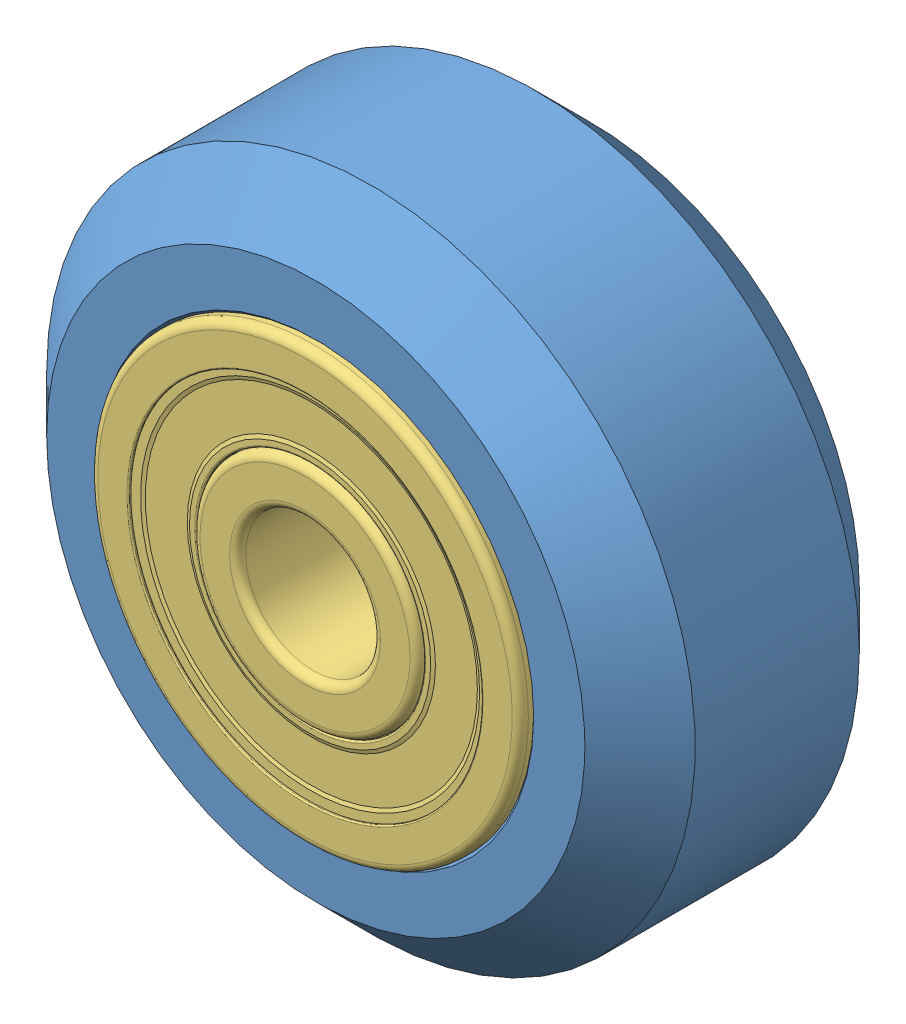
SolidWorks assembly V Wheel Component, configuration 默认. Lengths in mm.
Overall size (24.1 24.1 11.01).
4 component instances, 3 part files, 7 mates.
Components (placement in the parent):
- Rollers-1: Rollers [默认] at (1.8311 31.528 37.55) size (24.1 24.1 10.2)
- M5 washer1-1: M5 washer1 [默认] at (17.3311 -3.972 23.6) size (10 10 1)
- 625pillow-1: 625pillow [默认] at (17.3311 -3.972 21.1) x (0 0 1) z (-1 0 0) size (5.01 16 16)
- 625pillow-2: 625pillow [默认] at (17.3311 -3.972 27.1) x (0 0 -1) z (1 0 0) size (5.01 16 16)
Mates (geometry in assembly coordinates):
- 同心2: concentric anti-aligned: cylinder of Rollers-1 through (17.3311 -3.972 21.55) axis (0 0 1) radius 12.05; cylinder of M5 washer1-1 through (17.3311 -3.972 24.6) axis (0 0 -1) radius 5
- 距离2: distance = 4.6 mm aligned: plane of M5 washer1-1 through (17.3311 -3.972 24.6) normal (0 0 1); plane of Rollers-1 through (17.3311 -3.972 29.2) normal (0 0 1)
- 同心4: concentric aligned: cylinder of Rollers-1 through (17.3311 -3.972 21.55) axis (0 0 1) radius 12.05; cylinder of 625pillow-2 through (17.3311 -3.972 27.1) axis (0 0 1) radius 8
- 同心5: concentric anti-aligned: cylinder of Rollers-1 through (17.3311 -3.972 21.55) axis (0 0 1) radius 12.05; cylinder of 625pillow-1 through (17.3311 -3.972 21.1) axis (0 0 -1) radius 8
- 距离3: distance = 0 mm anti-aligned: plane of M5 washer1-1 through (17.3311 -3.972 23.6) normal (0 0 -1); plane of 625pillow-1 through (17.3311 -0.072 23.6) normal (0 0 1)
- 距离4: distance = 0 mm anti-aligned: plane of M5 washer1-1 through (17.3311 -3.972 24.6) normal (0 0 1); plane of 625pillow-2 through (17.3311 -0.072 24.6) normal (0 0 -1)
- 平行1: parallel anti-aligned: line of 625pillow-1 through (14.5025 -3.972 18.6) axis (1 0 0); line of 625pillow-2 through (20.1596 -3.972 29.6) axis (-1 0 0)
